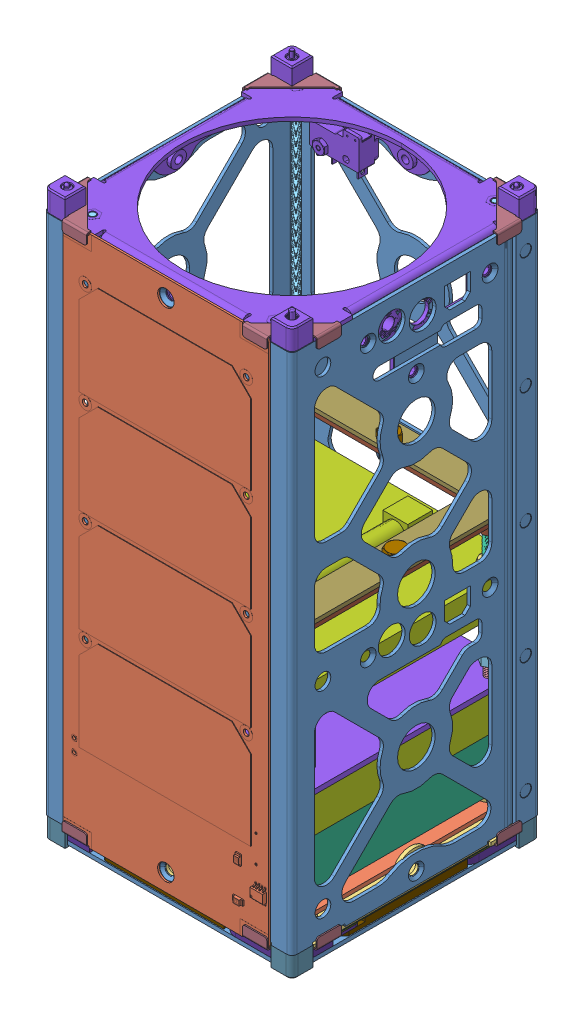
SolidWorks assembly FullAssembly_Simulation, configuration Default. Lengths in mm.
Overall size (102.54 229.61 102.54).
90 component instances, 26 part files, 157 mates.
Components (placement in the parent):
- 2U_Chassis_NoEnds-1: 2U_Chassis_NoEnds [Default] at (129.3638 156.9234 217.0115) size (100 209.95 100) (hidden)
- FirstAdapterPlate-1: FirstAdapterPlate [Default] at (79.3638 3.0787 167.0115) size (95.9 1.58 90.2)
- 5-40_nut-9: 5-40_nut [90760A130] at (36.5138 -0.4932 127.0115) size (6.35 2.87 7.33)
- 5-40_nut-10: 5-40_nut [90760A130] at (36.5138 1.888 127.0115) x (-0.837169 0 -0.546944) z (-0.546944 0 0.837169) size (6.35 2.87 7.33)
- ThreadedRod_1.25mm_2-1: ThreadedRod_1.25mm_2 [94435A506] at (122.2138 23.2162 204.5115) x (0 -1 0) z (0 0 1) size (64.19 3.19 3.69)
- ThreadedRod_1.25mm_2-2: ThreadedRod_1.25mm_2 [94435A506] at (36.5138 23.2162 127.0115) x (0 -1 0) z (0 0 1) size (64.19 3.19 3.69)
- ThreadedRod_1.25mm_2-3: ThreadedRod_1.25mm_2 [94435A506] at (122.2138 23.2162 130.8115) x (0 -1 0) z (0 0 1) size (64.19 3.19 3.69)
- ThreadedRod_1.25mm_2-4: ThreadedRod_1.25mm_2 [94435A506] at (36.5138 23.2162 207.0115) x (0 -1 0) z (0 0 1) size (64.19 3.19 3.69)
- 5-40_nut-11: 5-40_nut [90760A130] at (36.5138 1.888 207.0115) x (-0.837169 0 -0.546944) z (-0.546944 0 0.837169) size (6.35 2.87 7.33)
- 5-40_nut-12: 5-40_nut [90760A130] at (36.5138 -0.4932 207.0115) x (-1 0 0) z (0 0 -1) size (6.35 2.87 7.33)
- 5-40_nut-13: 5-40_nut [90760A130] at (122.2138 8.2305 204.5115) x (0.621448 0 0.783456) z (0.783456 0 -0.621448) size (6.35 2.87 7.33)
- 5-40_nut-14: 5-40_nut [90760A130] at (122.2138 5.8493 204.5115) x (-0.540526 0 0.841327) z (-0.841327 0 -0.540526) size (6.35 2.87 7.33)
- 5-40_nut-15: 5-40_nut [90760A130] at (122.2138 8.2305 130.8115) x (0.837169 0 0.546944) z (0.546944 0 -0.837169) size (6.35 2.87 7.33)
- 5-40_nut-16: 5-40_nut [90760A130] at (122.2138 5.8493 130.8115) x (-1 0 0) z (0 0 -1) size (6.35 2.87 7.33)
- 5-40_nut-17: 5-40_nut [90760A130] at (36.5138 5.8493 207.0115) x (-0.360727 0 0.932672) z (-0.932672 0 -0.360727) size (6.35 2.87 7.33)
- 5-40_nut-18: 5-40_nut [90760A130] at (36.5138 8.2305 127.0115) x (0.861208 0 0.508253) z (0.508253 0 -0.861208) size (6.35 2.87 7.33)
- 5-40_nut-19: 5-40_nut [90760A130] at (122.2138 -0.4932 204.5115) x (-1 0 0) z (0 0 -1) size (6.35 2.87 7.33)
- 5-40_nut-20: 5-40_nut [90760A130] at (36.5138 5.8493 127.0115) x (-1 0 0) z (0 0 -1) size (6.35 2.87 7.33)
- 5-40_nut-21: 5-40_nut [90760A130] at (122.2138 -0.4932 130.8115) x (-1 0 0) z (0 0 -1) size (6.35 2.87 7.33)
- 5-40_nut-22: 5-40_nut [90760A130] at (122.2138 1.888 130.8115) x (-0.837169 0 -0.546944) z (-0.546944 0 0.837169) size (6.35 2.87 7.33)
- 5-40_nut-23: 5-40_nut [90760A130] at (122.2138 1.888 204.5115) x (-0.837169 0 -0.546944) z (-0.546944 0 0.837169) size (6.35 2.87 7.33)
- 5-40_nut-24: 5-40_nut [90760A130] at (36.5138 8.2305 207.0115) x (0.837169 0 0.546944) z (0.546944 0 -0.837169) size (6.35 2.87 7.33)
- ThreadedRodAdapter-1: ThreadedRodAdapter [Default] at (122.2283 76.3162 204.4864) x (1 0 0) z (0 0 -1) size (6 20 5.2)
- ThreadedRodAdapter-2: ThreadedRodAdapter [Default] at (36.5283 76.3162 206.9864) x (1 0 0) z (0 0 -1) size (6 20 5.2)
- ThreadedRodAdapter-3: ThreadedRodAdapter [Default] at (122.2397 76.3162 130.7984) x (0.837169 0 0.546944) z (0.546944 0 -0.837169) size (6 20 5.2)
- ThreadedRodAdapter-4: ThreadedRodAdapter [Default] at (36.5283 76.3162 126.9864) x (1 0 0) z (0 0 -1) size (6 20 5.2)
- M4_ThreadedRod_Shortened-1: M4_ThreadedRod_Shortened [99055A110] at (122.2138 65.5162 204.5115) x (0 -1 0) z (-0.991936 0 -0.126738) size (42.53 3.77 4.24)
- M4_ThreadedRod_Shortened-2: M4_ThreadedRod_Shortened [99055A110] at (36.5138 65.5162 127.0115) x (0 -1 0) z (0.9699 0 -0.243505) size (42.53 3.77 4.24)
- M4_ThreadedRod_Shortened-3: M4_ThreadedRod_Shortened [99055A110] at (36.5138 65.5162 207.0115) x (0 -1 0) z (-0.548354 0 0.836246) size (42.53 3.77 4.24)
- M4_ThreadedRod_Shortened-4: M4_ThreadedRod_Shortened [99055A110] at (122.2138 65.5162 130.8115) x (0 -1 0) z (0.930349 0 -0.366676) size (42.53 3.77 4.24)
- CustomMagnetorquer-1: CustomMagnetorquer [Default] at (79.43 83.3162 167.0978) x (1 0 0.000843) z (-0.000843 0 1) size (95.9 29.64 90.3)
- 5-40_nut-25: 5-40_nut [90760A130] at (122.2138 86.1468 130.8115) x (0.837169 0 0.546944) z (0.546944 0 -0.837169) size (6.35 2.87 7.33)
- 5-40_nut-27: 5-40_nut [90760A130] at (36.5138 86.1468 127.0115) x (0.837169 0 0.546944) z (0.546944 0 -0.837169) size (6.35 2.87 7.33)
- 5-40_nut-28: 5-40_nut [90760A130] at (122.2138 86.1468 204.5115) x (0.837169 0 0.546944) z (0.546944 0 -0.837169) size (6.35 2.87 7.33)
- 5-40_nut-29: 5-40_nut [90760A130] at (36.5138 86.1468 207.0115) x (0.837169 0 0.546944) z (0.546944 0 -0.837169) size (6.35 2.87 7.33)
- Large_Aperature_Base_Plate.step-1: Large_Aperature_Base_Plate.step [Default] at (79.3638 206.6734 167.0115) x (-1 0 0) z (0 0 1) size (100 47.85 100)
- M4_Hex_Screw-1: M4_Hex_Screw [93635A104] at (121.3138 103.5762 167.0115) x (0 -1 0) z (-0.969186 0 0.24633) size (11.04 8.08 7)
- M4_Hex_Screw-2: M4_Hex_Screw [93635A104] at (37.4138 103.5762 167.0115) x (0 -1 0) z (-0.962943 0 -0.269706) size (11.04 8.08 7)
- M4_Hex_Screw-3: M4_Hex_Screw [93635A104] at (79.3638 103.5762 206.1115) x (0 -1 0) z (0.946217 0 0.323534) size (11.04 8.08 7)
- M4_Hex_Screw-4: M4_Hex_Screw [93635A104] at (79.3638 103.5762 127.9115) x (0 -1 0) z (-0.57376 0 0.819023) size (11.04 8.08 7)
- M4_Nut-1: M4_Nut [90710A035] at (37.4138 101.9162 167.0115) x (-0.396266 0 0.918136) z (-0.918136 0 -0.396266) size (7 2.75 8.08)
- M4_Nut-2: M4_Nut [90710A035] at (121.3138 101.9162 167.0115) x (-0.143588 0 0.989638) z (-0.989638 0 -0.143588) size (7 2.75 8.08)
- M4_Nut-3: M4_Nut [90710A035] at (79.3638 101.9162 206.1115) x (0.569583 0 0.821934) z (-0.821934 0 0.569583) size (7 2.75 8.08)
- M4_Nut-4: M4_Nut [90710A035] at (79.3638 101.9162 127.9115) x (0.466483 0 0.88453) z (-0.88453 0 0.466483) size (7 2.75 8.08)
- SecondAdapterPlate.1-3: SecondAdapterPlate.1 [Default] at (79.3638 104.5962 167.0115) x (1 0 0) z (0 0 -1) size (95.9 7.58 93.2)
- SecondAdapterPlate.2-2: SecondAdapterPlate.2 [Default] at (79.3638 104.5962 167.0115) x (-1 0 0) z (0 0 -1) size (95.9 7.58 93.2)
- SolarPanel_Clips.step-1: SolarPanel_Clips.step [Default] at (79.3624 -5.9176 167.0102) size (102.54 4.45 102.54)
- CoverPlate_Corners-2: CoverPlate_Corners [Default] at (79.3624 -4.6756 167.0102) x (1 0 0) z (0 1 0) size (99.75 99.75 8.54)
- EnduroSat_UHF_antenna+ZMTQ_SolarPanel-1: EnduroSat_UHF_antenna+ZMTQ_SolarPanel [Default] at (41.3132 62.8461 106.0387) x (1 0 0) z (0 -1 0) size (98.03 98.03 13.56)
  - EnduroSat_UHF_antenna+ZMTQ_SolarPanel.STEP-1: EnduroSat_UHF_antenna+ZMTQ_SolarPanel.STEP [Default] at origin size (98.03 98.03 13.56)
    - ES_UHF_Ant_Feed_v6_1.STEP-1: ES_UHF_Ant_Feed_v6_1.STEP [Default] at (37.8755 60.8085 69.6819) size (98 98 8.25)
    - ES_UHF_Ant_v6_1_Upper.STEP-1: ES_UHF_Ant_v6_1_Upper.STEP [Default] at (37.8755 60.8085 70.1842) size (98 98 0.5)
    - UHF_frame_Rev1.2_stepc.STEP-1: UHF_frame_Rev1.2_stepc.STEP [Default] at (37.8762 60.7984 70.1842) size (98.01 98.01 3)
    - vhf_uhf_door_19042017_2.STEP-1: vhf_uhf_door_19042017_2.STEP [Default] at (113.2674 3.9646 69.7842) x (0 1 0) z (0 0 1) size (53.47 9.32 3)
    - vhf_uhf_door_19042017_2.STEP-2: vhf_uhf_door_19042017_2.STEP [Default] at (94.7101 136.1895 69.7842) x (-1 0 0) z (0 0 1) size (53.47 9.32 3)
    - vhf_uhf_door_19042017_2.STEP-3: vhf_uhf_door_19042017_2.STEP [Default] at (-37.5149 117.6323 69.7842) x (0 -1 0) z (0 0 1) size (53.47 9.32 3)
    - vhf_uhf_door_19042017_2.STEP-4: vhf_uhf_door_19042017_2.STEP [Default] at (-18.9576 -14.5927 69.7842) x (1 0 0) z (0 0 1) size (53.47 9.32 3)
    - Top_Panel_Rev1_5_090617.STEP-1: Top_Panel_Rev1_5_090617.STEP [Default] at (37.8856 60.8034 74.7842) x (1 0.000204 0) z (0 0 1) size (98 98 8.6)
- SolarPanel_Clips.step-2: SolarPanel_Clips.step [Default] at (79.3638 206.6734 167.0115) x (1 0 0) z (0 0 -1) size (102.54 4.45 102.54)
- SolarPanel_2U_Side_Pumpkin.step-1: SolarPanel_2U_Side_Pumpkin.step [Default] at (79.3638 100.1605 216.9861) x (1 0 0) z (0 -1 0) size (82.55 6.14 214) (hidden)
- SolarPanel_2U_Side_Pumpkin.step-2: SolarPanel_2U_Side_Pumpkin.step [Default] at (129.3384 100.1605 167.0115) x (0 0 -1) z (0 -1 0) size (82.55 6.14 214) (hidden)
- SolarPanel_2U_Side_Pumpkin.step-4: SolarPanel_2U_Side_Pumpkin.step [Default] at (79.3638 100.1605 117.0369) x (-1 0 0) z (0 -1 0) size (82.55 6.14 214) (hidden)
- M_CoverPlate_Custom_Cut-1: M_CoverPlate_Custom_Cut [Default] at (79.3638 -6.3266 167.0115) size (100 14 100)
- M_ThreadedRod_1.25mm_1-1: M_ThreadedRod_1.25mm_1 [94435A506] at (49.3638 -30.8026 197.0115) x (0 -1 0) z (0 0 1) size (12.66 3.22 3.67)
- M_ThreadedRod_1.25mm_1-2: M_ThreadedRod_1.25mm_1 [94435A506] at (109.3638 -30.8026 197.0115) x (0 -1 0) z (0 0 1) size (12.66 3.22 3.67)
- M_ThreadedRod_1.25mm_1-3: M_ThreadedRod_1.25mm_1 [94435A506] at (49.3638 -30.8026 137.0115) x (0 -1 0) z (0 0 1) size (12.66 3.22 3.67)
- M_ThreadedRod_1.25mm_1-4: M_ThreadedRod_1.25mm_1 [94435A506] at (109.3638 -30.8026 137.0115) x (0 -1 0) z (0 0 1) size (12.66 3.22 3.67)
- 5-40_nut-30: 5-40_nut [90760A130] at (49.3638 1.888 137.0115) x (-0.837169 0 -0.546944) z (-0.546944 0 0.837169) size (6.35 2.87 7.33)
- 5-40_nut-31: 5-40_nut [90760A130] at (49.3638 1.888 197.0115) size (6.35 2.87 7.33)
- 5-40_nut-32: 5-40_nut [90760A130] at (109.3638 1.888 137.0115) size (6.35 2.87 7.33)
- 5-40_nut-33: 5-40_nut [90760A130] at (109.3638 5.8493 137.0115) x (-0.837169 0 -0.546944) z (-0.546944 0 0.837169) size (6.35 2.87 7.33)
- 5-40_nut-34: 5-40_nut [90760A130] at (109.3638 5.8493 197.0115) size (6.35 2.87 7.33)
- 5-40_nut-35: 5-40_nut [90760A130] at (109.3638 1.888 197.0115) size (6.35 2.87 7.33)
- 5-40_nut-36: 5-40_nut [90760A130] at (49.3638 5.8493 197.0115) size (6.35 2.87 7.33)
- 5-40_nut-37: 5-40_nut [90760A130] at (49.3638 5.8493 137.0115) size (6.35 2.87 7.33)
- M_M3_ThreadedRod-1: M_M3_ThreadedRod [Default] at (80.7505 116.7916 150.1828) x (0 1 0) z (0 0 1) size (101.43 3.04 3.46)
  - 90024A220_18-8 STAINLESS STEEL THREADED ROD-1: 90024A220_18-8 STAINLESS STEEL THREADED ROD [90024A220] at (26.8845 38.7417 59.6923) size (75.94 3.04 3.46)
  - 90024A220_18-8 STAINLESS STEEL THREADED ROD-2: 90024A220_18-8 STAINLESS STEEL THREADED ROD [90024A220] at (52.3745 38.7417 59.6923) size (75.94 3.04 3.46)
- M_M3_ThreadedRod-2: M_M3_ThreadedRod [Default] at (118.4438 196.0507 52.987) x (0 -1 0) z (-0.546944 0 0.837169) size (101.43 3.04 3.46)
  - 90024A220_18-8 STAINLESS STEEL THREADED ROD-1: 90024A220_18-8 STAINLESS STEEL THREADED ROD [90024A220] at (26.8845 38.7417 59.6923) size (75.94 3.04 3.46)
  - 90024A220_18-8 STAINLESS STEEL THREADED ROD-2: 90024A220_18-8 STAINLESS STEEL THREADED ROD [90024A220] at (52.3745 38.7417 59.6923) size (75.94 3.04 3.46)
- M_M3_ThreadedRod-3: M_M3_ThreadedRod [Default] at (115.9038 196.0507 138.712) x (0 -1 0) z (-0.546944 0 0.837169) size (101.43 3.04 3.46)
  - 90024A220_18-8 STAINLESS STEEL THREADED ROD-1: 90024A220_18-8 STAINLESS STEEL THREADED ROD [90024A220] at (26.8845 38.7417 59.6923) size (75.94 3.04 3.46)
  - 90024A220_18-8 STAINLESS STEEL THREADED ROD-2: 90024A220_18-8 STAINLESS STEEL THREADED ROD [90024A220] at (52.3745 38.7417 59.6923) size (75.94 3.04 3.46)
- M_M3_ThreadedRod-4: M_M3_ThreadedRod [Default] at (38.4338 196.0507 52.987) x (0 -1 0) z (-0.546944 0 0.837169) size (101.43 3.04 3.46)
  - 90024A220_18-8 STAINLESS STEEL THREADED ROD-1: 90024A220_18-8 STAINLESS STEEL THREADED ROD [90024A220] at (26.8845 38.7417 59.6923) size (75.94 3.04 3.46)
  - 90024A220_18-8 STAINLESS STEEL THREADED ROD-2: 90024A220_18-8 STAINLESS STEEL THREADED ROD [90024A220] at (52.3745 38.7417 59.6923) size (75.94 3.04 3.46)
- Battery-1: Battery [Default] at (79.3638 9.4212 167.0115) size (95 21.2 89.01)
- Transciever-1: Transciever [Default] at (79.3638 30.6212 167.0115) size (95 14.1 89.01)
- OBC-1: OBC [Default] at (79.3638 44.7212 167.0115) size (95 2 89.01)
Mates (geometry in assembly coordinates):
- Coincident13: coincident anti-aligned: plane of 5-40_nut-9 through (33.3388 0.6974 125.1785) normal (0 1 0); plane of 5-40_nut-10 through (40.1744 0.6974 127.2135) normal (0 -1 0)
- Concentric15: concentric aligned: circle of 5-40_nut-9; circle of 5-40_nut-10
- Concentric20: concentric aligned: circle of 5-40_nut-11; circle of 5-40_nut-12
- Coincident19: coincident anti-aligned: plane of 5-40_nut-11 through (40.1744 0.6974 207.2135) normal (0 -1 0); plane of 5-40_nut-12 through (39.6888 0.6974 208.8446) normal (0 1 0)
- Concentric21: concentric aligned: circle of 5-40_nut-13; circle of 5-40_nut-14
- Coincident20: coincident anti-aligned: plane of 5-40_nut-13 through (118.8046 7.0399 203.1632) normal (0 -1 0); plane of 5-40_nut-14 through (125.4722 7.0399 202.8312) normal (0 1 0)
- Concentric22: concentric aligned: circle of 5-40_nut-15; circle of 5-40_nut-16
- Coincident21: coincident anti-aligned: plane of 5-40_nut-15 through (118.5532 7.0399 130.6096) normal (0 -1 0); plane of 5-40_nut-16 through (125.3888 7.0399 132.6446) normal (0 1 0)
- Concentric23: concentric aligned: circle of 5-40_nut-19; circle of 5-40_nut-23
- Coincident22: coincident anti-aligned: plane of 5-40_nut-19 through (125.3888 0.6974 206.3446) normal (0 1 0); plane of 5-40_nut-23 through (125.8744 0.6974 204.7135) normal (0 -1 0)
- Concentric24: concentric aligned: circle of 5-40_nut-21; circle of 5-40_nut-22
- Coincident23: coincident anti-aligned: plane of 5-40_nut-21 through (125.3888 0.6974 132.6446) normal (0 1 0); plane of 5-40_nut-22 through (125.8744 0.6974 131.0135) normal (0 -1 0)
- Coincident24: coincident anti-aligned: plane of 5-40_nut-18 through (32.8478 7.0399 126.9765) normal (0 -1 0); plane of 5-40_nut-20 through (39.6888 7.0399 128.8446) normal (0 1 0)
- Concentric25: concentric aligned: circle of 5-40_nut-18; circle of 5-40_nut-20
- Coincident25: coincident anti-aligned: plane of 5-40_nut-17 through (39.3688 7.0399 204.7116) normal (0 1 0); plane of 5-40_nut-24 through (32.8532 7.0399 206.8096) normal (0 -1 0)
- Concentric26: concentric aligned: circle of 5-40_nut-17; circle of 5-40_nut-24
- Coincident26: coincident anti-aligned: plane of FirstAdapterPlate-1 through (79.3638 3.0787 167.0115) normal (0 -1 0); plane of 5-40_nut-22 through (125.8744 3.0787 131.0135) normal (0 1 0)
- Coincident27: coincident anti-aligned: plane of FirstAdapterPlate-1 through (79.3638 3.0787 167.0115) normal (0 -1 0); plane of 5-40_nut-10 through (40.1744 3.0787 127.2135) normal (0 1 0)
- Coincident28: coincident anti-aligned: plane of FirstAdapterPlate-1 through (79.3638 3.0787 167.0115) normal (0 -1 0); plane of 5-40_nut-11 through (40.1744 3.0787 207.2135) normal (0 1 0)
- Coincident29: coincident anti-aligned: plane of FirstAdapterPlate-1 through (79.3638 3.0787 167.0115) normal (0 -1 0); plane of 5-40_nut-23 through (125.8744 3.0787 204.7135) normal (0 1 0)
- Concentric27: concentric anti-aligned: circle of FirstAdapterPlate-1; circle of 5-40_nut-12
- Concentric28: concentric aligned: circle of FirstAdapterPlate-1; circle of 5-40_nut-21
- Concentric29: concentric anti-aligned: circle of FirstAdapterPlate-1; circle of 5-40_nut-9
- Concentric30: concentric anti-aligned: circle of FirstAdapterPlate-1; circle of 5-40_nut-19
- Coincident31: coincident aligned: plane of ThreadedRod_1.25mm_2-1 through (122.2138 -1.6838 204.5115) normal (0 -1 0); plane of 5-40_nut-19 through (125.3888 -1.6838 206.3446) normal (0 -1 0)
- Concentric31: concentric anti-aligned: circle of ThreadedRod_1.25mm_2-1; circle of 5-40_nut-19
- Coincident32: coincident aligned: plane of ThreadedRod_1.25mm_2-3 through (122.2138 -1.6838 130.8115) normal (0 -1 0); plane of 5-40_nut-21 through (125.3888 -1.6838 132.6446) normal (0 -1 0)
- Concentric32: concentric anti-aligned: circle of ThreadedRod_1.25mm_2-3; circle of 5-40_nut-21
- Coincident33: coincident aligned: plane of ThreadedRod_1.25mm_2-4 through (36.5138 -1.6838 207.0115) normal (0 -1 0); plane of 5-40_nut-12 through (39.6888 -1.6838 208.8446) normal (0 -1 0)
- Concentric33: concentric anti-aligned: circle of ThreadedRod_1.25mm_2-4; circle of 5-40_nut-12
- Coincident34: coincident aligned: plane of 5-40_nut-9 through (33.3388 -1.6838 125.1785) normal (0 -1 0); plane of ThreadedRod_1.25mm_2-2 through (36.5138 -1.6838 127.0115) normal (0 -1 0)
- Concentric34: concentric anti-aligned: circle of 5-40_nut-9; circle of ThreadedRod_1.25mm_2-2
- Concentric36: concentric anti-aligned: circle of ThreadedRod_1.25mm_2-4; circle of 5-40_nut-17
- Concentric37: concentric anti-aligned: circle of ThreadedRod_1.25mm_2-2; circle of 5-40_nut-20
- Concentric38: concentric anti-aligned: circle of ThreadedRod_1.25mm_2-3; circle of 5-40_nut-16
- Concentric39: concentric anti-aligned: circle of ThreadedRod_1.25mm_2-1; circle of 5-40_nut-14
- Concentric46: concentric anti-aligned: circle of ThreadedRod_1.25mm_2-1; circle of ThreadedRodAdapter-1
- Distance6: distance = 10 mm aligned: plane of ThreadedRod_1.25mm_2-1 through (122.2138 61.3162 204.5115) normal (0 1 0); plane of ThreadedRodAdapter-1 through (122.2283 71.3162 204.4864) normal (0 1 0)
- Concentric47: concentric anti-aligned: circle of ThreadedRod_1.25mm_2-3; circle of ThreadedRodAdapter-3
- Distance7: distance = 10 mm aligned: plane of ThreadedRodAdapter-3 through (122.2397 71.3162 130.7984) normal (0 1 0); plane of ThreadedRod_1.25mm_2-3 through (122.2138 61.3162 130.8115) normal (0 1 0)
- Concentric48: concentric anti-aligned: circle of ThreadedRod_1.25mm_2-4; circle of ThreadedRodAdapter-2
- Distance8: distance = 10 mm aligned: plane of ThreadedRod_1.25mm_2-4 through (36.5138 61.3162 207.0115) normal (0 1 0); plane of ThreadedRodAdapter-2 through (36.5283 71.3162 206.9864) normal (0 1 0)
- Concentric49: concentric anti-aligned: circle of ThreadedRod_1.25mm_2-2; circle of ThreadedRodAdapter-4
- Distance9: distance = 10 mm aligned: plane of ThreadedRod_1.25mm_2-2 through (36.5138 61.3162 127.0115) normal (0 1 0); plane of ThreadedRodAdapter-4 through (36.5283 71.3162 126.9864) normal (0 1 0)
- Concentric50: concentric aligned: circle of ThreadedRodAdapter-1; circle of M4_ThreadedRod_Shortened-1
- Distance10: distance = 10 mm anti-aligned: plane of M4_ThreadedRod_Shortened-1 through (122.2138 61.3162 204.5115) normal (0 -1 0); plane of ThreadedRodAdapter-1 through (122.2283 71.3162 204.4864) normal (0 1 0)
- Concentric51: concentric aligned: circle of ThreadedRodAdapter-2; circle of M4_ThreadedRod_Shortened-3
- Coincident46: coincident anti-aligned: plane of ThreadedRod_1.25mm_2-4 through (36.5138 61.3162 207.0115) normal (0 1 0); plane of M4_ThreadedRod_Shortened-3 through (36.5138 61.3162 207.0115) normal (0 -1 0)
- Concentric52: concentric aligned: circle of ThreadedRodAdapter-3; circle of M4_ThreadedRod_Shortened-4
- Coincident47: coincident anti-aligned: plane of ThreadedRod_1.25mm_2-3 through (122.2138 61.3162 130.8115) normal (0 1 0); plane of M4_ThreadedRod_Shortened-4 through (122.2138 61.3162 130.8115) normal (0 -1 0)
- Concentric53: concentric aligned: circle of ThreadedRodAdapter-4; circle of M4_ThreadedRod_Shortened-2
- Coincident48: coincident anti-aligned: plane of ThreadedRod_1.25mm_2-2 through (36.5138 61.3162 127.0115) normal (0 1 0); plane of M4_ThreadedRod_Shortened-2 through (36.5138 61.3162 127.0115) normal (0 -1 0)
- Concentric60: concentric anti-aligned: circle of M4_ThreadedRod_Shortened-2; circle of CustomMagnetorquer-1
- Coincident51: coincident anti-aligned: plane of ThreadedRodAdapter-2 through (36.5283 71.3162 206.9864) normal (0 1 0); plane of CustomMagnetorquer-1 through (79.43 71.3162 167.0978) normal (0 -1 0)
- Concentric63: concentric aligned: circle of M4_ThreadedRod_Shortened-3; circle of 5-40_nut-29
- Coincident52: coincident anti-aligned: plane of CustomMagnetorquer-1 through (79.43 84.9562 167.0978) normal (0 1 0); plane of 5-40_nut-29 through (32.8532 84.9562 206.8096) normal (0 -1 0)
- Concentric64: concentric aligned: circle of M4_ThreadedRod_Shortened-2; circle of 5-40_nut-27
- Coincident53: coincident anti-aligned: plane of CustomMagnetorquer-1 through (79.43 84.9562 167.0978) normal (0 1 0); plane of 5-40_nut-27 through (32.8532 84.9562 126.8096) normal (0 -1 0)
- Concentric65: concentric aligned: circle of M4_ThreadedRod_Shortened-1; circle of 5-40_nut-28
- Coincident54: coincident anti-aligned: plane of CustomMagnetorquer-1 through (79.43 84.9562 167.0978) normal (0 1 0); plane of 5-40_nut-28 through (118.5532 84.9562 204.3096) normal (0 -1 0)
- Concentric66: concentric aligned: circle of M4_ThreadedRod_Shortened-4; circle of 5-40_nut-25
- Coincident55: coincident anti-aligned: plane of CustomMagnetorquer-1 through (79.43 84.9562 167.0978) normal (0 1 0); plane of 5-40_nut-25 through (118.5532 84.9562 130.6096) normal (0 -1 0)
- Concentric86: concentric aligned: circle of 2U_Chassis_NoEnds-1; circle of Large_Aperature_Base_Plate.step-1
- Concentric87: concentric aligned: circle of 2U_Chassis_NoEnds-1; circle of Large_Aperature_Base_Plate.step-1
- Concentric88: concentric aligned: circle of M4_ThreadedRod_Shortened-4; circle of SecondAdapterPlate.1-3
- Coincident110: coincident anti-aligned: plane of M4_ThreadedRod_Shortened-2 through (36.5138 103.0162 127.0115) normal (0 1 0); plane of SecondAdapterPlate.1-3 through (79.3638 103.0162 167.0115) normal (0 -1 0)
- Concentric89: concentric aligned: circle of M4_ThreadedRod_Shortened-2; circle of SecondAdapterPlate.1-3
- Coincident114: coincident anti-aligned: plane of M4_Hex_Screw-3 through (75.3983 106.1762 206.8912) normal (0 -1 0); plane of SecondAdapterPlate.2-2 through (79.3638 106.1762 167.0115) normal (0 1 0)
- Concentric94: concentric aligned: circle of M4_Hex_Screw-3; circle of SecondAdapterPlate.2-2
- Coincident115: coincident anti-aligned: plane of M4_Nut-4 through (79.5185 103.0162 123.8731) normal (0 1 0); plane of SecondAdapterPlate.1-3 through (79.3638 103.0162 167.0115) normal (0 -1 0)
- Concentric95: concentric aligned: circle of M4_Nut-4; circle of SecondAdapterPlate.1-3
- Coincident116: coincident anti-aligned: plane of M4_Hex_Screw-1 through (124.2082 106.1762 164.1909) normal (0 -1 0); plane of SecondAdapterPlate.2-2 through (79.3638 106.1762 167.0115) normal (0 1 0)
- Concentric96: concentric aligned: circle of M4_Hex_Screw-1; circle of SecondAdapterPlate.2-2
- Coincident117: coincident anti-aligned: plane of M4_Nut-1 through (40.656 103.0162 164.5988) normal (0 1 0); plane of SecondAdapterPlate.1-3 through (79.3638 103.0162 167.0115) normal (0 -1 0)
- Concentric97: concentric aligned: circle of M4_Nut-1; circle of SecondAdapterPlate.1-3
- Concentric98: concentric aligned: circle of M4_Hex_Screw-2; circle of SecondAdapterPlate.2-2
- Coincident118: coincident anti-aligned: plane of M4_Hex_Screw-2 through (41.3291 106.1762 166.0097) normal (0 -1 0); plane of SecondAdapterPlate.2-2 through (79.3638 106.1762 167.0115) normal (0 1 0)
- Concentric99: concentric aligned: circle of M4_Nut-2; circle of SecondAdapterPlate.1-3
- Coincident119: coincident anti-aligned: plane of M4_Nut-2 through (123.8161 103.0162 163.838) normal (0 1 0); plane of SecondAdapterPlate.1-3 through (79.3638 103.0162 167.0115) normal (0 -1 0)
- Concentric100: concentric aligned: circle of M4_Hex_Screw-4; circle of SecondAdapterPlate.2-2
- Coincident120: coincident anti-aligned: plane of M4_Hex_Screw-4 through (79.7169 106.1762 123.8856) normal (0 -1 0); plane of SecondAdapterPlate.2-2 through (79.3638 106.1762 167.0115) normal (0 1 0)
- Coincident121: coincident anti-aligned: plane of M4_Nut-3 through (79.0312 103.0162 202.0838) normal (0 1 0); plane of SecondAdapterPlate.1-3 through (79.3638 103.0162 167.0115) normal (0 -1 0)
- Concentric101: concentric aligned: circle of M4_Nut-3; circle of SecondAdapterPlate.1-3
- Coincident126: coincident anti-aligned: plane of SecondAdapterPlate.1-3 through (79.3638 104.5962 167.0115) normal (0 1 0); plane of SecondAdapterPlate.2-2 through (79.3638 104.5962 167.0115) normal (0 -1 0)
- Coincident127: coincident anti-aligned: circle of SecondAdapterPlate.1-3; circle of SecondAdapterPlate.2-2
- Coincident128: coincident anti-aligned: circle of SecondAdapterPlate.1-3; circle of SecondAdapterPlate.2-2
- Concentric109: concentric aligned: circle of SolarPanel_Clips.step-1; circle of CoverPlate_Corners-2
- Coincident131: coincident: plane of 2U_Chassis_NoEnds-1 through (31.3958 -4.8026 214.9795) normal (0 -1 0); plane of CoverPlate_Corners-2 through (32.1945 -4.8026 214.1781) normal (0 1 0)
- Parallel2: parallel anti-aligned: plane of CoverPlate_Corners-2 through (37.9894 -13.1996 125.6372) normal (1 0 0); plane of EnduroSat_UHF_antenna+ZMTQ_SolarPanel-1/EnduroSat_UHF_antenna+ZMTQ_SolarPanel.STEP-1/UHF_frame_Rev1.2_stepc.STEP-1 through (37.9894 -10.338 125.1372) normal (-1 0 0)
- Coincident134: coincident anti-aligned: plane of CoverPlate_Corners-2 through (37.9894 -13.1996 125.6372) normal (1 0 0); plane of EnduroSat_UHF_antenna+ZMTQ_SolarPanel-1/EnduroSat_UHF_antenna+ZMTQ_SolarPanel.STEP-1/UHF_frame_Rev1.2_stepc.STEP-1 through (37.9894 -10.338 125.1372) normal (-1 0 0)
- Coincident135: coincident anti-aligned: plane of CoverPlate_Corners-2 through (29.4894 -13.1996 125.6372) normal (0 0 1); plane of EnduroSat_UHF_antenna+ZMTQ_SolarPanel-1/EnduroSat_UHF_antenna+ZMTQ_SolarPanel.STEP-1/UHF_frame_Rev1.2_stepc.STEP-1 through (30.1894 -10.338 125.6372) normal (0 0 -1)
- Concentric111: concentric anti-aligned: circle of Large_Aperature_Base_Plate.step-1; circle of SolarPanel_Clips.step-2
- Coincident136: coincident anti-aligned: plane of Large_Aperature_Base_Plate.step-1 through (127.9668 206.6734 118.4085) normal (0 1 0); plane of SolarPanel_Clips.step-2 through (110.0493 206.6734 217.0115) normal (0 -1 0)
- Parallel3: parallel anti-aligned: plane of 2U_Chassis_NoEnds-1 through (129.3638 89.17 315.1419) normal (1 0 0); plane of SolarPanel_Clips.step-2 through (130.1258 207.1814 212.6209) normal (-1 0 0)
- Concentric112: concentric anti-aligned: circle of 2U_Chassis_NoEnds-1; circle of SolarPanel_2U_Side_Pumpkin.step-1
- Coincident138: coincident anti-aligned: plane of SolarPanel_Clips.step-2 through (33.7545 207.1814 217.7735) normal (0 0 -1); plane of SolarPanel_2U_Side_Pumpkin.step-1 through (79.3638 100.1605 217.7735) normal (0 0 1)
- Parallel4: parallel aligned: line of SolarPanel_Clips.step-2 through (120.4992 203.727 218.2815) axis (0 1 0); line of SolarPanel_2U_Side_Pumpkin.step-1 through (120.6388 201.316 217.7735) axis (0 1 0)
- Concentric115: concentric anti-aligned: circle of 2U_Chassis_NoEnds-1; circle of SolarPanel_2U_Side_Pumpkin.step-2
- Coincident141: coincident anti-aligned: plane of SolarPanel_Clips.step-2 through (130.1258 207.1814 212.6209) normal (-1 0 0); plane of SolarPanel_2U_Side_Pumpkin.step-2 through (130.1258 100.1605 167.0115) normal (1 0 0)
- Parallel5: parallel anti-aligned: line of SolarPanel_Clips.step-2 through (130.6338 203.727 208.1469) axis (0 1 0); line of SolarPanel_2U_Side_Pumpkin.step-2 through (130.1004 201.316 208.2865) axis (0 -1 0)
- Concentric117: concentric anti-aligned: circle of 2U_Chassis_NoEnds-1; circle of SolarPanel_2U_Side_Pumpkin.step-4
- Coincident144: coincident anti-aligned: plane of SolarPanel_Clips.step-2 through (124.9731 207.1814 116.2495) normal (0 0 1); plane of SolarPanel_2U_Side_Pumpkin.step-4 through (79.3638 100.1605 116.2495) normal (0 0 -1)
- Parallel6: parallel anti-aligned: line of SolarPanel_Clips.step-2 through (120.4992 203.727 115.7415) axis (0 1 0); line of SolarPanel_2U_Side_Pumpkin.step-4 through (120.6388 201.316 116.2749) axis (0 -1 0)
- Concentric118: concentric: circle of CoverPlate_Corners-2; circle of M_CoverPlate_Custom_Cut-1
- Coincident145: coincident anti-aligned: plane of EnduroSat_UHF_antenna+ZMTQ_SolarPanel-1/EnduroSat_UHF_antenna+ZMTQ_SolarPanel.STEP-1/ES_UHF_Ant_Feed_v6_1.STEP-1 through (30.1887 -6.3266 125.8472) normal (0 1 0); plane of M_CoverPlate_Custom_Cut-1 through (79.3638 -6.3266 167.0115) normal (0 -1 0)
- Parallel7: parallel aligned: plane of EnduroSat_UHF_antenna+ZMTQ_SolarPanel-1/EnduroSat_UHF_antenna+ZMTQ_SolarPanel.STEP-1/vhf_uhf_door_19042017_2.STEP-4 through (22.3556 -9.938 215.8371) normal (0 0 1); plane of M_CoverPlate_Custom_Cut-1 through (109.3638 7.6734 216.0115) normal (0 0 1)
- Coincident146: coincident anti-aligned: plane of M_CoverPlate_Custom_Cut-1 through (79.3638 -4.8026 167.0115) normal (0 1 0); plane of M_ThreadedRod_1.25mm_1-1 through (49.3638 -4.8026 197.0115) normal (0 -1 0)
- Concentric119: concentric aligned: circle of M_CoverPlate_Custom_Cut-1; circle of M_ThreadedRod_1.25mm_1-1
- Coincident147: coincident anti-aligned: plane of M_CoverPlate_Custom_Cut-1 through (79.3638 -4.8026 167.0115) normal (0 1 0); plane of M_ThreadedRod_1.25mm_1-2 through (109.3638 -4.8026 197.0115) normal (0 -1 0)
- Concentric120: concentric aligned: circle of M_CoverPlate_Custom_Cut-1; circle of M_ThreadedRod_1.25mm_1-2
- Coincident148: coincident anti-aligned: plane of M_CoverPlate_Custom_Cut-1 through (79.3638 -4.8026 167.0115) normal (0 1 0); plane of M_ThreadedRod_1.25mm_1-4 through (109.3638 -4.8026 137.0115) normal (0 -1 0)
- Concentric121: concentric aligned: circle of M_CoverPlate_Custom_Cut-1; circle of M_ThreadedRod_1.25mm_1-4
- Coincident149: coincident anti-aligned: plane of M_CoverPlate_Custom_Cut-1 through (79.3638 -4.8026 167.0115) normal (0 1 0); plane of M_ThreadedRod_1.25mm_1-3 through (49.3638 -4.8026 137.0115) normal (0 -1 0)
- Concentric122: concentric aligned: circle of M_CoverPlate_Custom_Cut-1; circle of M_ThreadedRod_1.25mm_1-3
- Concentric123: concentric aligned: circle of FirstAdapterPlate-1; circle of M_ThreadedRod_1.25mm_1-4
- Concentric124: concentric aligned: circle of FirstAdapterPlate-1; circle of M_ThreadedRod_1.25mm_1-1
- Concentric125: concentric aligned: circle of M_CoverPlate_Custom_Cut-1; circle of 5-40_nut-32
- Coincident151: coincident anti-aligned: plane of M_CoverPlate_Custom_Cut-1 through (109.3638 0.6974 137.0115) normal (0 1 0); plane of 5-40_nut-32 through (106.1888 0.6974 135.1785) normal (0 -1 0)
- Coincident152: coincident anti-aligned: plane of M_CoverPlate_Custom_Cut-1 through (49.3638 0.6974 137.0115) normal (0 1 0); plane of 5-40_nut-30 through (53.0244 0.6974 137.2135) normal (0 -1 0)
- Concentric127: concentric aligned: circle of M_CoverPlate_Custom_Cut-1; circle of 5-40_nut-30
- Coincident154: coincident anti-aligned: plane of M_CoverPlate_Custom_Cut-1 through (109.3638 0.6974 197.0115) normal (0 1 0); plane of 5-40_nut-35 through (106.1888 0.6974 195.1785) normal (0 -1 0)
- Concentric128: concentric aligned: circle of M_CoverPlate_Custom_Cut-1; circle of 5-40_nut-35
- Coincident155: coincident anti-aligned: plane of M_CoverPlate_Custom_Cut-1 through (49.3638 0.6974 197.0115) normal (0 1 0); plane of 5-40_nut-31 through (46.1888 0.6974 195.1785) normal (0 -1 0)
- Concentric129: concentric aligned: circle of M_CoverPlate_Custom_Cut-1; circle of 5-40_nut-31
- Coincident156: coincident anti-aligned: plane of FirstAdapterPlate-1 through (79.3638 3.0787 167.0115) normal (0 -1 0); plane of 5-40_nut-32 through (106.1888 3.0787 135.1785) normal (0 1 0)
- Coincident161: coincident anti-aligned: plane of FirstAdapterPlate-1 through (79.3638 4.6587 167.0115) normal (0 1 0); plane of 5-40_nut-33 through (113.0244 4.6587 137.2135) normal (0 -1 0)
- Coincident162: coincident anti-aligned: plane of FirstAdapterPlate-1 through (79.3638 4.6587 167.0115) normal (0 1 0); plane of 5-40_nut-34 through (106.1888 4.6587 195.1785) normal (0 -1 0)
- Coincident163: coincident anti-aligned: plane of FirstAdapterPlate-1 through (79.3638 4.6587 167.0115) normal (0 1 0); plane of 5-40_nut-36 through (46.1888 4.6587 195.1785) normal (0 -1 0)
- Coincident164: coincident anti-aligned: plane of FirstAdapterPlate-1 through (79.3638 4.6587 167.0115) normal (0 1 0); plane of 5-40_nut-37 through (46.1888 4.6587 135.1785) normal (0 -1 0)
- Concentric130: concentric aligned: circle of M_ThreadedRod_1.25mm_1-3; circle of 5-40_nut-37
- Concentric131: concentric aligned: circle of M_ThreadedRod_1.25mm_1-1; circle of 5-40_nut-36
- Concentric132: concentric aligned: circle of M_ThreadedRod_1.25mm_1-2; circle of 5-40_nut-34
- Concentric133: concentric aligned: circle of M_ThreadedRod_1.25mm_1-4; circle of 5-40_nut-33
- Coincident166: coincident: plane of SolarPanel_Clips.step-1 through (110.0479 -5.9176 117.0102) normal (0 1 0); plane of M_CoverPlate_Custom_Cut-1 through (79.3638 -6.3266 167.0115) normal (0 -1 0)
- Coincident167: coincident: plane of SolarPanel_Clips.step-1 through (110.0479 -6.4256 117.0102) normal (0 -1 0); plane of CoverPlate_Corners-2 through (79.3624 -6.4256 167.0102) normal (0 1 0)
- Concentric139: concentric: circle of 2U_Chassis_NoEnds-1; circle of M_CoverPlate_Custom_Cut-1
- Coincident168: coincident anti-aligned: plane of SecondAdapterPlate.2-2 through (79.3638 106.1762 167.0115) normal (0 1 0); plane of M_M3_ThreadedRod-1/90024A220_18-8 STAINLESS STEEL THREADED ROD-1 through (42.0088 106.1762 209.875) normal (0 -1 0)
- Concentric140: concentric aligned: circle of SecondAdapterPlate.2-2; circle of M_M3_ThreadedRod-1/90024A220_18-8 STAINLESS STEEL THREADED ROD-2
- Coincident169: coincident anti-aligned: plane of SecondAdapterPlate.2-2 through (79.3638 106.1762 167.0115) normal (0 1 0); plane of M_M3_ThreadedRod-3/90024A220_18-8 STAINLESS STEEL THREADED ROD-2 through (115.6888 106.1762 209.874) normal (0 -1 0)
- Coincident170: coincident anti-aligned: plane of SecondAdapterPlate.2-2 through (79.3638 106.1762 167.0115) normal (0 1 0); plane of M_M3_ThreadedRod-4/90024A220_18-8 STAINLESS STEEL THREADED ROD-2 through (38.2188 106.1762 124.149) normal (0 -1 0)
- Coincident171: coincident anti-aligned: plane of SecondAdapterPlate.2-2 through (79.3638 106.1762 167.0115) normal (0 1 0); plane of M_M3_ThreadedRod-2/90024A220_18-8 STAINLESS STEEL THREADED ROD-2 through (118.2288 106.1762 124.149) normal (0 -1 0)
- Concentric141: concentric aligned: circle of SecondAdapterPlate.2-2; circle of M_M3_ThreadedRod-3/90024A220_18-8 STAINLESS STEEL THREADED ROD-1
- Concentric142: concentric aligned: circle of SecondAdapterPlate.2-2; circle of M_M3_ThreadedRod-2/90024A220_18-8 STAINLESS STEEL THREADED ROD-1
- Concentric143: concentric aligned: circle of SecondAdapterPlate.2-2; circle of M_M3_ThreadedRod-4/90024A220_18-8 STAINLESS STEEL THREADED ROD-1
- Concentric144: concentric aligned: circle of 5-40_nut-24; circle of Battery-1
- Coincident172: coincident anti-aligned: plane of 5-40_nut-24 through (32.8532 9.4212 206.8096) normal (0 1 0); plane of Battery-1 through (79.3638 9.4212 167.0115) normal (0 -1 0)
- Concentric145: concentric aligned: circle of 5-40_nut-18; circle of Battery-1
- Concentric146: concentric aligned: circle of 5-40_nut-29; circle of Transciever-1
- Coincident174: coincident anti-aligned: plane of Battery-1 through (79.3638 30.6212 167.0115) normal (0 1 0); plane of Transciever-1 through (79.3638 30.6212 167.0115) normal (0 -1 0)
- Concentric147: concentric aligned: circle of 5-40_nut-25; circle of Transciever-1
- Concentric148: concentric aligned: circle of 5-40_nut-29; circle of OBC-1
- Coincident175: coincident anti-aligned: plane of Transciever-1 through (79.3638 44.7212 167.0115) normal (0 1 0); plane of OBC-1 through (79.3638 44.7212 167.0115) normal (0 -1 0)
- Concentric149: concentric aligned: circle of 5-40_nut-25; circle of OBC-1
- Coincident176: coincident anti-aligned: plane of 5-40_nut-18 through (32.8478 9.4212 126.9765) normal (0 1 0); plane of Battery-1 through (79.3638 9.4212 167.0115) normal (0 -1 0)
- Coincident177: coincident anti-aligned: plane of 5-40_nut-15 through (118.5532 9.4212 130.6096) normal (0 1 0); plane of Battery-1 through (79.3638 9.4212 167.0115) normal (0 -1 0)
- Coincident178: coincident anti-aligned: plane of 5-40_nut-13 through (118.8046 9.4212 203.1632) normal (0 1 0); plane of Battery-1 through (79.3638 9.4212 167.0115) normal (0 -1 0)
- Coincident179: coincident anti-aligned: plane of FirstAdapterPlate-1 through (79.3638 4.6587 167.0115) normal (0 1 0); plane of 5-40_nut-14 through (125.4722 4.6587 202.8312) normal (0 -1 0)
